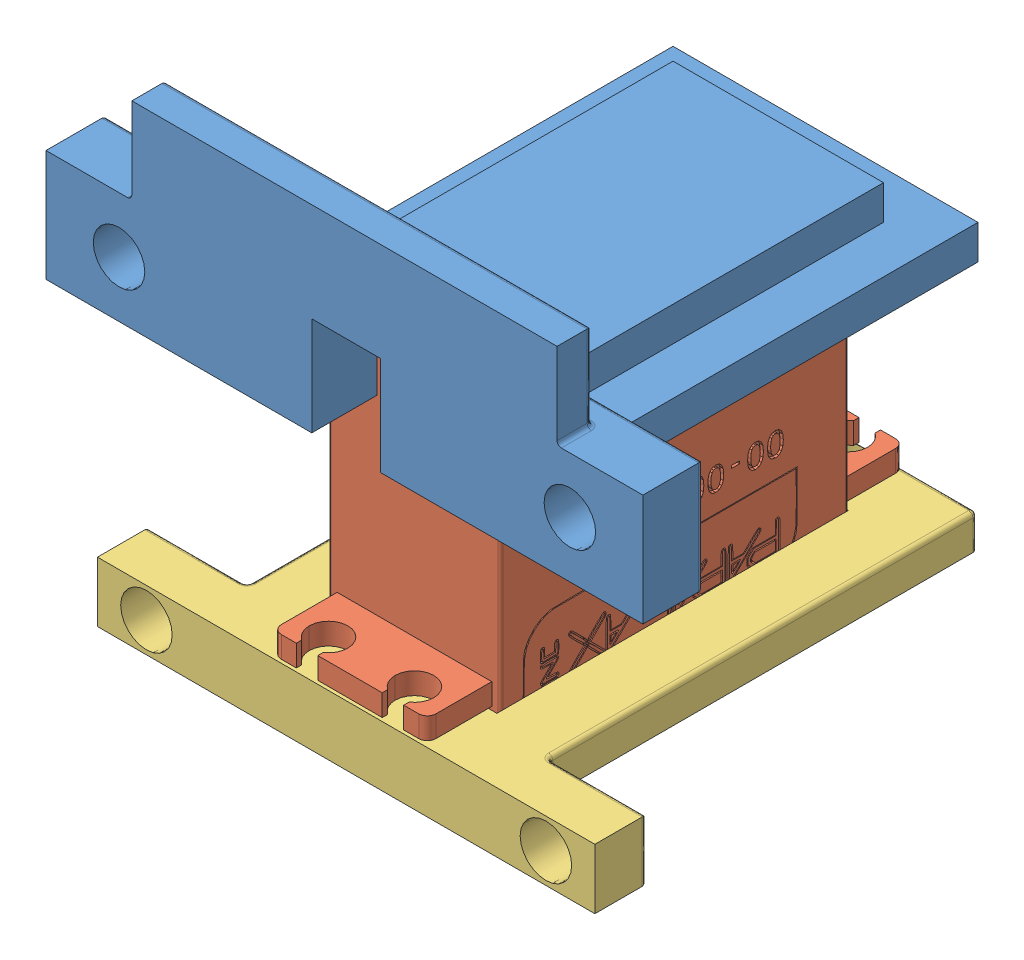
SolidWorks assembly bras pompe sans bras, configuration Défaut. Lengths in mm.
Overall size (69.48 68.28 56).
3 component instances, 3 part files, 6 mates.
Components (placement in the parent):
- soutien-servo-fond M4 INSERT BIEN-1: soutien-servo-fond M4 INSERT BIEN [Défaut] at (9.3033 -10.6738 68.9819) size (69.48 23 56)
- Parallax Servo 900-00005-1: Parallax Servo 900-00005 [Défaut] at (3.2033 -6.6738 48.9819) x (1 0 0) z (0 -1 0) size (20.01 55.5 42.1)
- soutien-servo M4 INSERT BIEN-1: soutien-servo M4 INSERT BIEN [Défaut] at (-3.2967 -35.7738 68.8819) x (-1 0 0) z (0 0 1) size (57.9 20.18 55.9)
Mates (geometry in assembly coordinates):
- Coïncidente1: coincident: plane of soutien-servo-fond M4 INSERT BIEN-1 through (9.3033 -6.6738 68.9819) normal (0 -1 0); plane of Parallax Servo 900-00005-1 through (3.2033 -6.6738 48.9819) normal (0 1 0)
- Coïncidente2: coincident: plane of soutien-servo-fond M4 INSERT BIEN-1 through (-6.7967 -6.6738 68.9819) normal (1 0 0); plane of Parallax Servo 900-00005-1 through (-6.7967 -6.6738 48.9819) normal (-1 0 0)
- Coïncidente3: coincident anti-aligned: plane of soutien-servo-fond M4 INSERT BIEN-1 through (9.3033 -6.6738 48.9819) normal (0 0 1); plane of Parallax Servo 900-00005-1 through (3.2033 -42.7738 48.9819) normal (0 0 -1)
- Coïncidente4: coincident: plane of Parallax Servo 900-00005-1 through (3.2033 -35.7738 48.9819) normal (0 -1 0); plane of soutien-servo M4 INSERT BIEN-1 through (-3.2967 -35.7738 68.8819) normal (0 1 0)
- Coïncidente5: coincident: plane of Parallax Servo 900-00005-1 through (13.2033 -6.6738 48.9819) normal (1 0 0); plane of soutien-servo M4 INSERT BIEN-1 through (13.2033 -39.7738 48.9819) normal (-1 0 0)
- Coïncidente6: coincident anti-aligned: plane of Parallax Servo 900-00005-1 through (3.2033 -42.7738 48.9819) normal (0 0 -1); plane of soutien-servo M4 INSERT BIEN-1 through (-6.8967 -39.7738 48.9819) normal (0 0 1)
